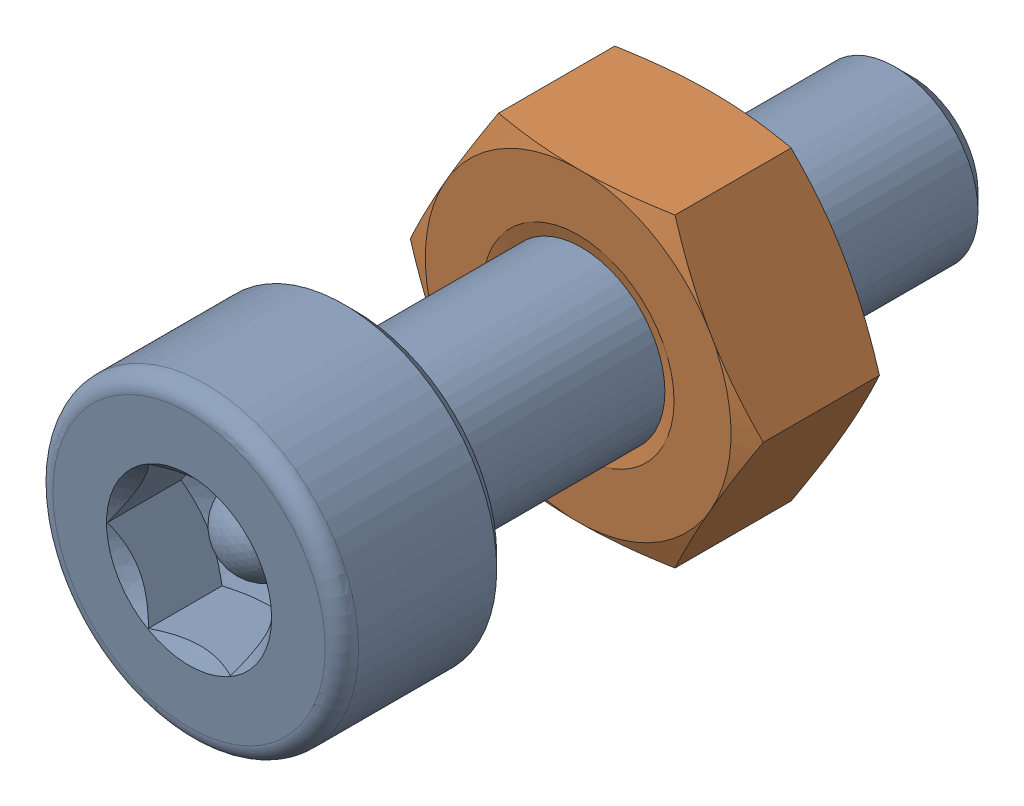
SolidWorks assembly Screw and Nut M3x010_014, configuration Varsayılan. Lengths in mm.
Overall size (6.35 5.5 13.14).
2 component instances, 2 part files, 0 mates.
Components (placement in the parent):
- M3x10-Screw013-1: M3x10-Screw013 [Varsayılan] at origin size (5.5 5.5 13.14)
- M3-Nut045-1: M3-Nut045 [Varsayılan] at (0 0 -4) x (-1 0 0) z (0 0 -1) size (6.35 5.5 2.4)
